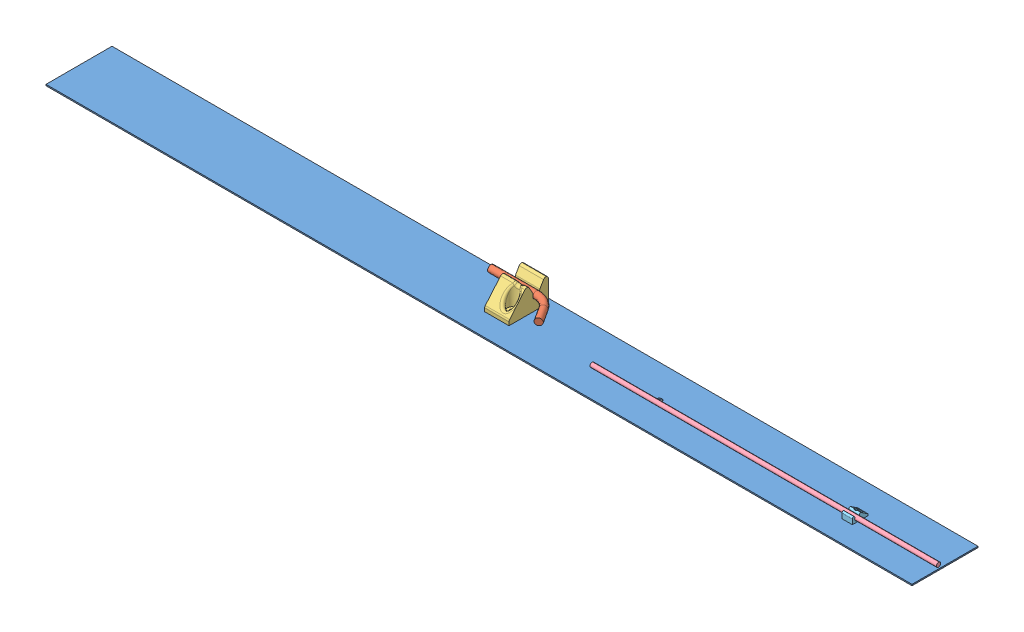
SolidWorks assembly Hood Prop rod holder, configuration Default. Lengths in mm.
Overall size (1000 42.61 76.2).
5 component instances, 5 part files, 13 mates.
Components (placement in the parent):
- Engine Bay hood arm holder cutout-2: Engine Bay hood arm holder cutout [Default] at origin size (1000 1.5 76.2)
- Part1^Hood Prop rod holder-1: Part1^Hood Prop rod holder [Default] at origin size (84.22 7.77 31.83) (virtual)
- GMC Safari Hood Prop Arm Clip-1: GMC Safari Hood Prop Arm Clip [Default] at (0 0.75 0) x (1 0 0) z (0 1 0) size (28.07 45.45 42.61)
- Part4^Hood Prop rod holder-1: Part4^Hood Prop rod holder [Default] at (500 0 0) x (0 0 -1) z (1 0 0) size (5.05 5.05 400) (virtual)
- Hood Cable Clip-1: Hood Cable Clip [Default] at (0 0.75 0) x (1 0 0) z (0 1 0) size (12 18 12.76)
Mates (geometry in assembly coordinates):
- Coincident1: coordinate: unknown of Engine Bay hood arm holder cutout-2
- InPlace1: in place: plane of ? through (0 0.75 0) normal (0 1 0); plane of ? through (0 0.75 0) normal (0 1 0); moOrthogonalPlaneRef_w of ? through (0 0.75 0) normal (0 1 0); plane of ? through (0 0.75 0) normal (0 0 -1); plane of ? through (0 0.75 0) normal (0 1 0); plane of ? through (0 0.75 0) normal (1 0 0); plane of ? through (0 0.75 0) normal (0 1 0); unknown of ?
- Coincident2: coincident aligned: plane of ?; plane of ?
- Coincident3: coincident aligned: moOrthogonalPlaneRef_w of Engine Bay hood arm holder cutout-2 through (0 0.75 0) normal (0 0 -1); plane of GMC Safari Hood Prop Arm Clip-1 through (0 0.75 0) normal (0 0 -1)
- Coincident4: coincident anti-aligned: moOrthogonalPlaneRef_w of Engine Bay hood arm holder cutout-2 through (0 0.75 0) normal (-1 0 0); plane of GMC Safari Hood Prop Arm Clip-1 through (0 0.75 0) normal (1 0 0)
- InPlace2: in place: plane of ? through (500 0.75 -38.1) normal (1 0 0); plane of Part4^Hood Prop rod holder-1 through (500 0 0) normal (1 0 0); plane of ? through (500 0.75 -38.1) normal (1 0 0); plane of Part4^Hood Prop rod holder-1 through (500 0 0) normal (0 1 0); plane of ? through (500 0.75 -38.1) normal (1 0 0); plane of Part4^Hood Prop rod holder-1 through (500 0 0) normal (0 0 -1); plane of ? through (500 0.75 -38.1) normal (1 0 0); unknown of Part4^Hood Prop rod holder-1
- Coincident5: coincident aligned: plane of assembly through (500 0.75 -38.1) normal (1 0 0); plane of assembly through (500 0 0) normal (1 0 0)
- Coincident6: coincident aligned: moOrthogonalPlaneRef_w of Engine Bay hood arm holder cutout-2 through (500 0 0) normal (0 1 0); plane of Part4^Hood Prop rod holder-1 through (500 0 0) normal (0 1 0)
- Coincident7: coincident anti-aligned: moOrthogonalPlaneRef_w of Engine Bay hood arm holder cutout-2 through (500 0 0) normal (0 0 1); plane of Part4^Hood Prop rod holder-1 through (500 0 0) normal (0 0 -1)
- InPlace3: in place: plane of ? through (0 0.75 0) normal (0 1 0); plane of ? through (0 0.75 0) normal (0 1 0); plane of ? through (0 0.75 0) normal (0 1 0); plane of ? through (0 0.75 0) normal (0 0 -1); plane of ? through (0 0.75 0) normal (0 1 0); plane of ? through (0 0.75 0) normal (1 0 0); plane of ? through (0 0.75 0) normal (0 1 0); unknown of ?
- Coincident8: coincident aligned: plane of ?; plane of ?
- Coincident9: coincident aligned: moOrthogonalPlaneRef_w of Engine Bay hood arm holder cutout-2 through (0 0.75 0) normal (0 0 -1); plane of Part5^Hood Prop rod holder-1 through (0 0.75 0) normal (0 0 -1)
- Coincident10: coincident anti-aligned: moOrthogonalPlaneRef_w of Engine Bay hood arm holder cutout-2 through (0 0.75 0) normal (-1 0 0); plane of Part5^Hood Prop rod holder-1 through (0 0.75 0) normal (1 0 0)
